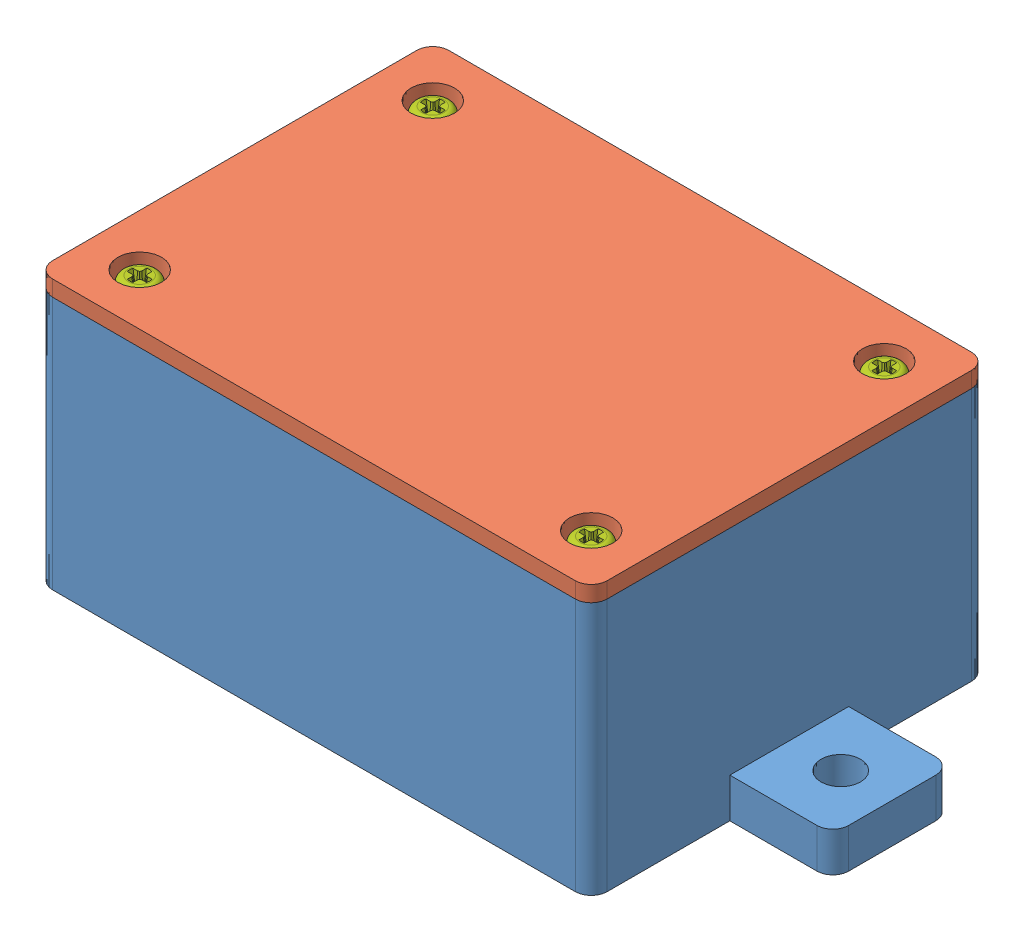
SolidWorks assembly VoyageCase, configuration Default. Lengths in mm.
Overall size (121.92 43.18 63.5).
17 component instances, 8 part files, 36 mates.
Components (placement in the parent):
- Case-1: Case [Default] at (26.8088 14.203 76.2154) size (121.92 40.64 63.5)
- Lid-1: Lid [Default] at (26.8088 57.383 76.2154) x (1 0 0) z (0 0 -1) size (88.9 13.97 63.5)
- 3x6mmStandoff-1: 3x6mmStandoff [92080A004] at (-10.0212 24.553 76.2154) x (-0.945158 0 0.326614) z (0 1 0) size (4.5 5.2 8.36)
- 3x6mmStandoff-2: 3x6mmStandoff [92080A004] at (63.6388 24.553 76.2154) x (0.612617 0 0.79038) z (0 -1 0) size (4.5 5.2 8.36)
- Adafruit PermaProto Half Sized-1: Adafruit PermaProto Half Sized [Default] at (26.8088 28.553 76.2154) x (-1 0 0) z (0 0 -1) size (81.28 1.68 50.8)
- Photon - Solidworks-1: Photon - Solidworks [Default<As Machined>] at (2.4629 39.3785 76.2662) x (0 0 1) z (-1 0 0) size (20.42 4.2 37.4)
- 3mmNut-1: 3mmNut [93369A116] at (-9.3862 47.708 52.7204) size (5.7 3.08 6.58)
- 3mmNut-2: 3mmNut [93369A116] at (63.0038 47.708 99.7104) size (5.7 3.08 6.58)
- 3mmNut-3: 3mmNut [93369A116] at (-9.3862 47.708 99.7104) size (5.7 3.08 6.58)
- 3mmNut-5: 3mmNut [93369A116] at (63.0038 47.708 52.7204) size (5.7 3.08 6.58)
- 3x8mmScrew-5: 3x8mmScrew [94879A118] at (-9.3862 54.208 52.7204) x (1 0 0) z (0 1 0) size (5.6 5.71 10.83)
- 3x8mmScrew-6: 3x8mmScrew [94879A118] at (63.0038 54.208 52.7204) x (1 0 0) z (0 1 0) size (5.6 5.71 10.83)
- 3x8mmScrew-8: 3x8mmScrew [94879A118] at (-9.3862 54.208 99.7104) x (1 0 0) z (0 1 0) size (5.6 5.71 10.83)
- 3x8mmScrew-9: 3x8mmScrew [94879A118] at (63.0038 54.208 99.7104) x (1 0 0) z (0 1 0) size (5.6 5.71 10.83)
- Photon - Solidworks-2: Photon - Solidworks [Default<As Machined>] at (40.4994 39.3785 76.1646) x (0 0 1) z (-1 0 0) size (20.42 4.2 37.4)
- 3x6mmScrrew-1: 3x6mmScrrew [94879A887] at (63.6388 16.953 76.2154) x (1 0 0) z (0 -1 0) size (5.6 5.71 6.81)
- 3x6mmScrrew-2: 3x6mmScrrew [94879A887] at (-10.0212 16.953 76.2154) x (1 0 0) z (0 -1 0) size (5.6 5.71 6.81)
Mates (geometry in assembly coordinates):
- Coincident1: coincident anti-aligned: plane of Case-1 through (26.8088 54.843 76.2154) normal (0 1 0); plane of Lid-1 through (26.8088 54.843 76.2154) normal (0 -1 0)
- Coincident2: coincident anti-aligned: plane of Case-1 through (-14.4662 54.843 47.6404) normal (0 0 1); plane of Lid-1 through (-14.4662 51.668 47.6404) normal (0 0 -1)
- Coincident4: coincident anti-aligned: axis of Case-1 through (-9.3862 49.258 99.7104) axis (0 1 0); axis of Lid-1 through (-9.3862 54.208 99.7104) axis (0 -1 0)
- Coincident5: coincident anti-aligned: axis of Case-1 through (-10.0212 16.953 76.2154) axis (0 1 0); axis of 3x6mmStandoff-1 through (-10.0212 28.4985 76.2154) axis (0 -1 0)
- Coincident6: coincident anti-aligned: plane of Case-1 through (26.8088 20.553 76.2154) normal (0 1 0); plane of 3x6mmStandoff-1 through (-9.1727 20.553 78.671) normal (0 -1 0)
- Coincident7: coincident anti-aligned: plane of Case-1 through (26.8088 20.553 76.2154) normal (0 1 0); plane of 3x6mmStandoff-2 through (61.5853 20.553 77.8071) normal (0 -1 0)
- Coincident8: coincident aligned: axis of Case-1 through (63.6388 16.953 76.2154) axis (0 1 0); axis of 3x6mmStandoff-2 through (63.6388 20.6074 76.2154) axis (0 1 0)
- Coincident10: coincident aligned: axis of Case-1 through (-10.0212 16.953 76.2154) axis (0 1 0); axis of Adafruit PermaProto Half Sized-1 through (-10.0212 28.553 76.2154) axis (0 1 0)
- Coincident11: coincident aligned: axis of Case-1 through (63.6388 16.953 76.2154) axis (0 1 0); axis of Adafruit PermaProto Half Sized-1 through (63.6388 28.553 76.2154) axis (0 1 0)
- Coincident13: coincident anti-aligned: plane of 3x6mmStandoff-2 through (61.5853 28.553 77.8071) normal (0 1 0); plane of Adafruit PermaProto Half Sized-1 through (26.8088 28.553 76.2154) normal (0 -1 0)
- Coincident18: coincident aligned: axis of Adafruit PermaProto Half Sized-1 through (-9.9577 28.553 67.3254) axis (0 1 0); axis of Photon - Solidworks-1 through (-9.9577 38.553 67.3254) axis (0 1 0)
- Distance2: distance = 10 mm aligned: plane of Photon - Solidworks-1 through (2.4629 40.1786 76.2662) normal (0 1 0); plane of Adafruit PermaProto Half Sized-1 through (26.8088 30.1786 76.2154) normal (0 1 0)
- Parallel5: parallel aligned: plane of Case-1 through (-17.6412 54.843 107.9654) normal (-1 0 0); plane of Photon - Solidworks-1 through (-14.1995 40.1786 66.0554) normal (-1 0 0)
- Coincident21: coincident anti-aligned: plane of 3mmNut-1 through (-12.2362 46.458 51.075) normal (0 -1 0); plane of assembly through (0 46.458 0) normal (0 1 0)
- Coincident22: coincident anti-aligned: axis of Case-1 through (-9.3862 49.258 52.7204) axis (0 1 0); axis of 3mmNut-1 through (-9.3862 48.958 52.7204) axis (0 -1 0)
- Coincident23: coincident anti-aligned: plane of 3mmNut-5 through (60.1538 46.458 51.075) normal (0 -1 0); plane of assembly through (0 46.458 0) normal (0 1 0)
- Coincident24: coincident aligned: plane of 3mmNut-3 through (-12.2362 46.458 98.065) normal (0 -1 0); plane of 3mmNut-5 through (60.1538 46.458 51.075) normal (0 -1 0)
- Coincident25: coincident aligned: plane of 3mmNut-2 through (60.1538 46.458 98.065) normal (0 -1 0); plane of 3mmNut-3 through (-12.2362 46.458 98.065) normal (0 -1 0)
- Coincident26: coincident anti-aligned: axis of Case-1 through (63.0038 49.258 52.7204) axis (0 1 0); axis of 3mmNut-5 through (63.0038 48.958 52.7204) axis (0 -1 0)
- Coincident27: coincident anti-aligned: axis of Case-1 through (-9.3862 49.258 99.7104) axis (0 1 0); axis of 3mmNut-3 through (-9.3862 48.958 99.7104) axis (0 -1 0)
- Coincident28: coincident anti-aligned: axis of Case-1 through (63.0038 49.258 99.7104) axis (0 1 0); axis of 3mmNut-2 through (63.0038 48.958 99.7104) axis (0 -1 0)
- Coincident50: coincident anti-aligned: plane of Lid-1 through (-9.3862 54.208 52.7204) normal (0 1 0); plane of 3x8mmScrew-5 through (-9.3862 54.208 52.7204) normal (0 -1 0)
- Coincident51: coincident anti-aligned: plane of Lid-1 through (63.0038 54.208 52.7204) normal (0 1 0); plane of 3x8mmScrew-6 through (63.0038 54.208 52.7204) normal (0 -1 0)
- Coincident52: coincident aligned: plane of 3x8mmScrew-8 through (-9.3862 54.208 99.7104) normal (0 -1 0); plane of 3x8mmScrew-9 through (63.0038 54.208 99.7104) normal (0 -1 0)
- Coincident53: coincident anti-aligned: plane of Lid-1 through (63.0038 54.208 99.7104) normal (0 1 0); plane of 3x8mmScrew-9 through (63.0038 54.208 99.7104) normal (0 -1 0)
- Coincident54: coincident aligned: axis of Case-1 through (63.0038 49.258 99.7104) axis (0 1 0); line of 3x8mmScrew-9 through (63.0038 54.208 99.7104) axis (0 1 0)
- Coincident55: coincident aligned: axis of Case-1 through (63.0038 49.258 52.7204) axis (0 1 0); line of 3x8mmScrew-6 through (63.0038 54.208 52.7204) axis (0 1 0)
- Coincident56: coincident aligned: axis of Case-1 through (-9.3862 49.258 99.7104) axis (0 1 0); line of 3x8mmScrew-8 through (-9.3862 54.208 99.7104) axis (0 1 0)
- Coincident57: coincident anti-aligned: axis of 3mmNut-1 through (-9.3862 48.958 52.7204) axis (0 -1 0); line of 3x8mmScrew-5 through (-9.3862 54.208 52.7204) axis (0 1 0)
- Coincident59: coincident aligned: plane of Photon - Solidworks-1 through (2.4629 40.1786 76.2662) normal (0 1 0); plane of Photon - Solidworks-2 through (40.4994 40.1786 76.1646) normal (0 1 0)
- Parallel6: parallel aligned: plane of Case-1 through (-17.6412 54.843 107.9654) normal (-1 0 0); plane of Photon - Solidworks-2 through (23.837 40.1786 65.9538) normal (-1 0 0)
- Coincident62: coincident aligned: axis of Adafruit PermaProto Half Sized-1 through (56.0188 29.8264 85.1054) axis (0 1 0); axis of Photon - Solidworks-2 through (56.0188 38.553 85.1054) axis (0 1 0)
- Coincident66: coincident: plane of Case-1 through (-10.0212 16.953 76.2154) normal (0 -1 0); plane of 3x6mmScrrew-2 through (-10.0212 16.953 76.2154) normal (0 1 0)
- Coincident67: coincident anti-aligned: axis of Case-1 through (-10.0212 16.953 76.2154) axis (0 -1 0); axis of 3x6mmScrrew-2 through (-10.0212 15.573 76.2154) axis (0 1 0)
- Coincident68: coincident: plane of Case-1 through (63.6388 16.953 76.2154) normal (0 -1 0); plane of 3x6mmScrrew-1 through (63.6388 16.953 76.2154) normal (0 1 0)
- Coincident69: coincident anti-aligned: axis of Case-1 through (63.6388 16.953 76.2154) axis (0 -1 0); axis of 3x6mmScrrew-1 through (63.6388 15.573 76.2154) axis (0 1 0)
